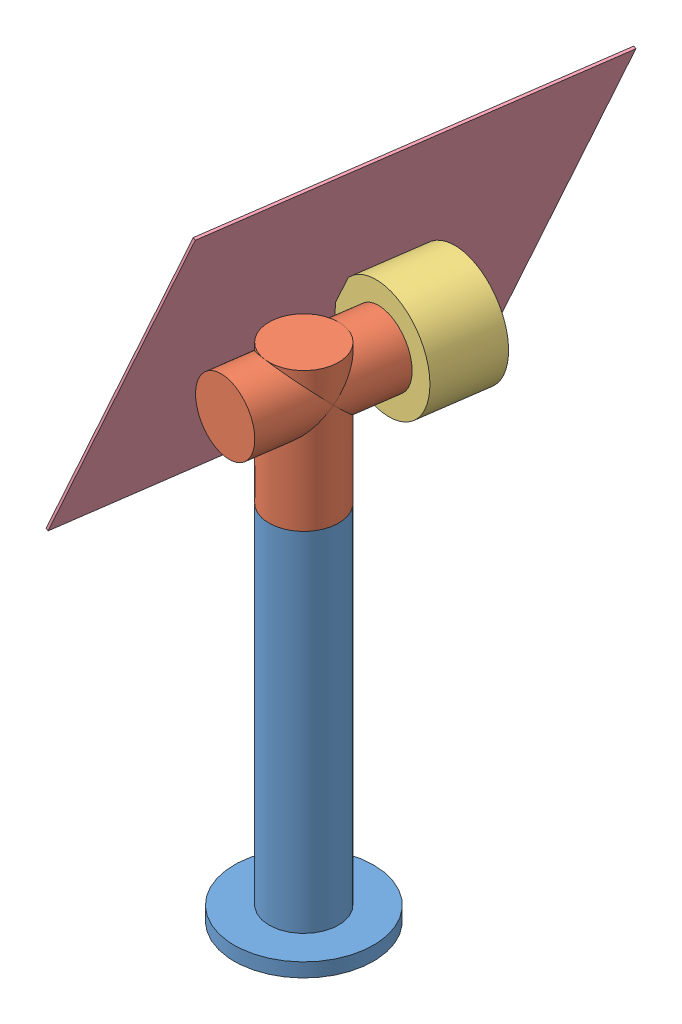
SolidWorks assembly Aparelho, configuration Default. Lengths in mm.
Overall size (176.61 478.21 294.83).
4 component instances, 4 part files, 7 mates.
Components (placement in the parent):
- Parte de baixo-1: Parte de baixo [Default] at (103.2542 134.0657 197.3971) size (100 260 100)
- Parte_meio-1: Parte_meio [Default] at (103.2542 494.0657 197.3971) x (0.990209 0 0.139591) z (0.139591 0 -0.990209) size (50 100 100)
- Parte_cima-1: Parte_cima [Default] at (117.2133 469.0657 98.3762) x (-0.43943 -0.896138 -0.061947) z (-0.887364 0.443775 -0.125093) size (80 50 80)
- PainelSolar-1: PainelSolar [Default] at (-4.7265 360.5585 273.0648) x (-0.139591 0 0.990209) z (-0.43943 -0.896138 -0.061947) size (280 1.8 280)
Mates (geometry in assembly coordinates):
- Coincident1: coincident anti-aligned: plane of Parte de baixo-1 through (103.2542 394.0657 197.3971) normal (0 1 0); plane of Parte_meio-1 through (103.2542 394.0657 197.3971) normal (0 -1 0)
- Concentric1: concentric anti-aligned: cylinder of Parte de baixo-1 through (103.2542 394.0657 197.3971) axis (0 -1 0) radius 25; cylinder of Parte_meio-1 through (103.2542 394.0657 197.3971) axis (0 1 0) radius 25
- Coincident2: coincident anti-aligned: plane of Parte_meio-1 through (110.2338 469.0657 147.8867) normal (0.139591 0 -0.990209); plane of Parte_cima-1 through (110.2338 469.0657 147.8867) normal (-0.139591 0 0.990209)
- Concentric2: concentric aligned: cylinder of Parte_meio-1 through (96.2747 469.0657 246.9076) axis (0.139591 0 -0.990209) radius 25; cylinder of Parte_cima-1 through (110.2338 469.0657 147.8867) axis (0.139591 0 -0.990209) radius 40
- Distance1: distance = 40 mm aligned: plane of Parte_cima-1 through (117.2133 469.0657 98.3762) normal (-0.887364 0.443775 -0.125093); plane of PainelSolar-1 through (-6.3237 361.3573 272.8397) normal (-0.887364 0.443775 -0.125093)
- Distance2: distance = 190 mm aligned: plane of Parte_cima-1 through (117.2133 469.0657 98.3762) normal (-0.139591 0 0.990209); plane of PainelSolar-1 through (-4.7265 360.5585 273.0648) normal (-0.139591 0 0.990209)
- Distance3: distance = 140 mm aligned: plane of Parte_cima-1 through (117.2133 469.0657 98.3762) normal (-0.43943 -0.896138 -0.061947); plane of PainelSolar-1 through (-4.7265 360.5585 273.0648) normal (-0.43943 -0.896138 -0.061947)
